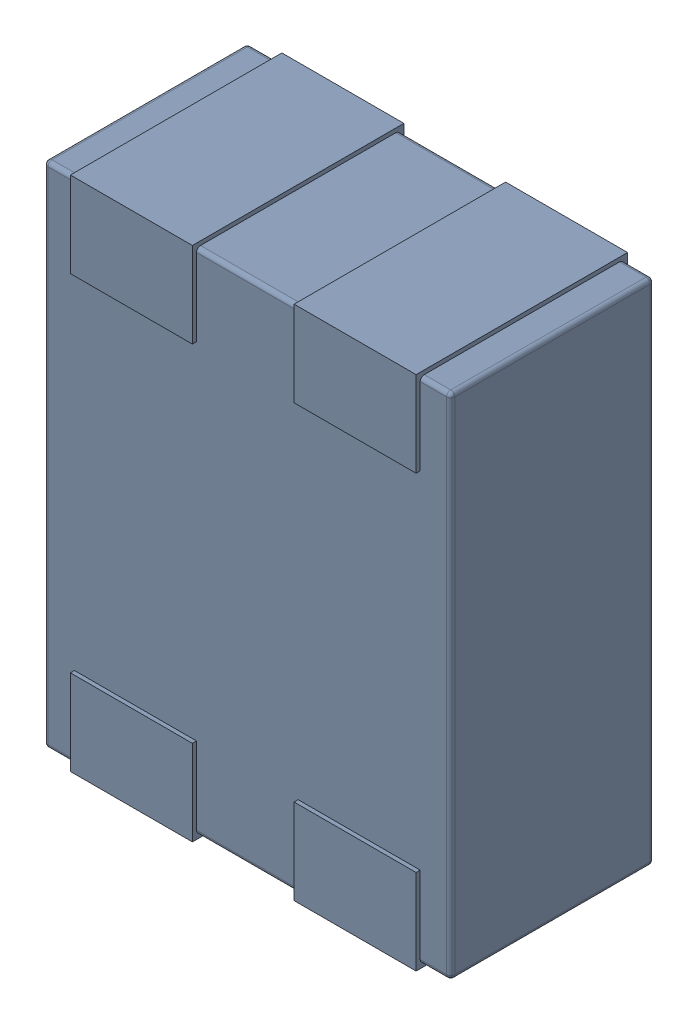
SolidWorks assembly L21, configuration Défaut. Lengths in mm.
Overall size (1 1.27 0.52).
4 component instances, 1 part files, 0 mates.
Components (placement in the parent):
- MCZ1210DH900L2TA0G-1: MCZ1210DH900L2TA0G [Défaut] at (57.6483 -40.4565 -1.6) x (-1 0 0) z (0 0 1) size (1 1.27 0.52)
  - 3D_PCB1_2021-12-30 (1).step-1: 3D_PCB1_2021-12-30 (1).step [Défaut] at origin size (1 1.27 0.52)
    - a3ec64f90eb5404ebd79eca0046a794a.step-1: a3ec64f90eb5404ebd79eca0046a794a.step [Défaut] at (5.0419 -6.8961 1.6) size (1 1.27 0.52)
      - SOLID.step_650-1: SOLID.step_650 [Défaut] at origin size (1 1.27 0.52)
